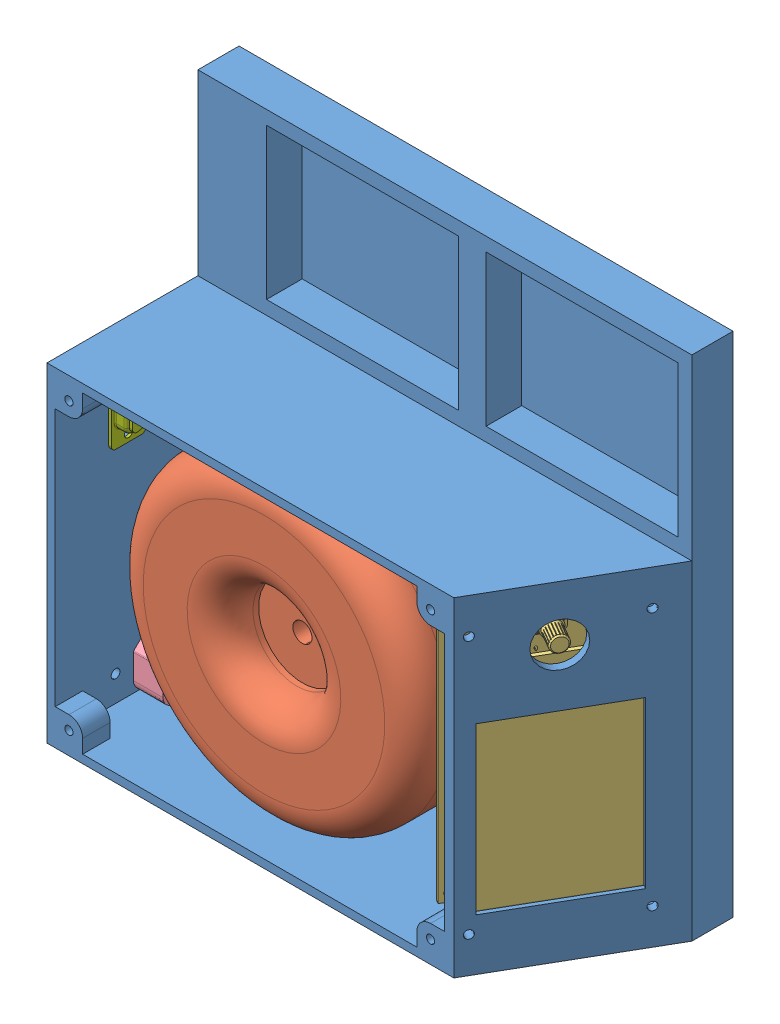
SolidWorks assembly Assem1, configuration Default. Lengths in mm.
Overall size (186.5 202.31 70).
7 component instances, 7 part files, 23 mates.
Components (placement in the parent):
- haz1-1: haz1 [Default] at origin size (180 185 70)
- Transformer-1: Transformer [Default] at (-18.4187 0 14.5) x (0.843543 0.537061 0) z (0 0 -1) size (112 112 54)
- JBC_SolderingIron-1: JBC_SolderingIron [Default] at (69.4239 -50 11.7589) x (0 1 0) z (0.866025 0 0.5) size (100 55 34.69)
- PowerConn-1: PowerConn [Default] at (-93.3 -47.6 28) x (0 0 1) z (-1 0 0) size (50 22.4 26.9)
- RPC1-12RB-6P-1: RPC1-12RB-6P [Default] at (-87 39.595 16.1) x (0 1 0) z (1 0 0) size (20.2 20.2 22.2)
- User Library-KCD11-1: User Library-KCD11 [Default] at (-81.3 -26.15 28) x (0 0 1) z (0 -1 0) size (15.06 19.01 10.5)
- D-Sub_9-1: D-Sub_9 [Default] at (-86.5 39.595 44.25) x (0 -1 0) z (-1 0 0) size (30.81 12.5 16.2)
Mates (geometry in assembly coordinates):
- Coincident1: coordinate: point of haz1-1; point of assembly
- Coincident2: coincident anti-aligned: plane of haz1-1 through (0 0 3) normal (0 0 1); plane of Transformer-1 through (-22.5 -0.2283 3) normal (0 0 -1)
- Coincident17: coincident anti-aligned: plane of haz1-1 through (66.2099 0 46.3607) normal (-0.819152 0 -0.573576); plane of JBC_SolderingIron-1 through (71.5757 -1.268 38.6974) normal (0.819152 0 0.573576)
- Width3: width anti-aligned: plane of JBC_SolderingIron-1 through (67.959 -50 10.9132) normal (0 -1 0); plane of JBC_SolderingIron-1 through (40.459 50 58.5446) normal (0 1 0); plane of haz1-1 through (-90 -57 70) normal (0 1 0); plane of haz1-1 through (-90 57 70) normal (0 -1 0)
- Coincident16: coincident anti-aligned: plane of haz1-1; plane of JBC_SolderingIron-1
- Distance11: distance = 60 mm: line of haz1-1 through (90 60 15) axis (0 -1 0); point of JBC_SolderingIron-1
- Coincident18: coincident anti-aligned: plane of haz1-1 through (-90 60 70) normal (-1 0 0); plane of PowerConn-1 through (-90 -47.6 28) normal (1 0 0)
- Tangent1: tangent anti-aligned: plane of haz1-1 through (0 0 3) normal (0 0 1); cylinder of PowerConn-1 through (-93.3 -47.6 8) axis (1 0 0) radius 5
- Coincident20: coincident anti-aligned: plane of haz1-1 through (-90 -57 70) normal (0 1 0); plane of PowerConn-1 through (-90 -57 41.5) normal (0 -1 0)
- Coincident23: coincident anti-aligned: plane of haz1-1 through (0 0 8.5) normal (0 0 1); plane of Transformer-1 through (-18.4187 0 8.5) normal (0 0 -1)
- Concentric4: concentric aligned: cylinder of Transformer-1 through (-18.4187 0 8.5) axis (0 0 1) radius 3.5; circle of haz1-1
- Coincident25: coincident anti-aligned: plane of haz1-1 through (-87 60 70) normal (1 0 0); plane of RPC1-12RB-6P-1 through (-87 39.595 16.1) normal (-1 0 0)
- Coincident26: coincident anti-aligned: plane of haz1-1 through (-90 60 70) normal (-1 0 0); plane of User Library-KCD11-1 through (-90 -31.4 20.5) normal (1 0 0)
- Parallel1: parallel anti-aligned: line of haz1-1 through (-90 -60 70) axis (0 0 -1); line of User Library-KCD11-1 through (-91 -31.4 20.5) axis (0 0 1)
- Width5: width anti-aligned: plane of PowerConn-1 through (-93.3 -36.4 13) normal (0 0 -1); plane of PowerConn-1 through (-93.3 -58.8 43) normal (0 0 1); plane of User Library-KCD11-1 through (-91.5 -20.9 35.5) normal (0 0 1); plane of User Library-KCD11-1 through (-91.5 -20.9 20.5) normal (0 0 -1)
- Distance15: distance = 5 mm anti-aligned: plane of User Library-KCD11-1 through (-91.5 -31.4 20.5) normal (0 -1 0); plane of PowerConn-1 through (-93.3 -36.4 43) normal (0 1 0)
- Coincident27: coincident anti-aligned: plane of haz1-1 through (-87 60 70) normal (1 0 0); plane of D-Sub_9-1 through (-87 39.595 44.25) normal (-1 0 0)
- Parallel3: parallel anti-aligned: plane of haz1-1 through (0 0 70) normal (0 0 1); plane of D-Sub_9-1 through (-120.2492 53.5 38) normal (0 0 -1)
- Distance17: distance = 2 mm anti-aligned: plane of D-Sub_9-1 through (-120.2492 55 49) normal (0 1 0); plane of haz1-1 through (-90 57 70) normal (0 -1 0)
- Distance18: distance = 35 mm anti-aligned: plane of D-Sub_9-1 through (-120.2492 53.5 38) normal (0 0 -1); plane of haz1-1 through (0 0 3) normal (0 0 1)
- Concentric7: concentric aligned: cylinder of haz1-1 through (-63.3112 46.845 23.35) axis (-1 0 0) radius 1.25; cylinder of RPC1-12RB-6P-1 through (-87 46.845 23.35) axis (-1 0 0) radius 1.25
- Concentric8: concentric aligned: cylinder of haz1-1 through (-63.3112 32.345 8.85) axis (-1 0 0) radius 1.25; cylinder of RPC1-12RB-6P-1 through (-87 32.345 8.85) axis (-1 0 0) radius 1.25
- Distance19: distance = 1.5 mm aligned: plane of JBC_SolderingIron-1 through (71.2103 -1.268 44.5447) normal (0.866025 0 0.5); plane of haz1-1 through (73.9952 60 42.7211) normal (0.866025 0 0.5)
